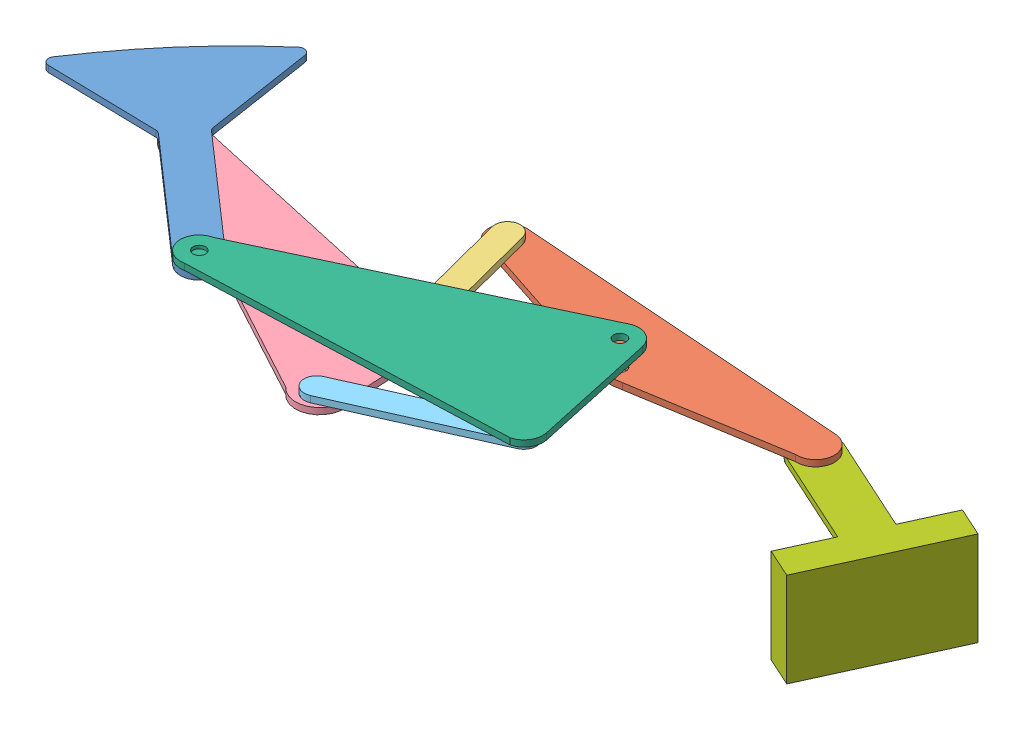
SolidWorks assembly Gait mechanism, configuration Default. Lengths in mm.
Overall size (136.77 20 51.26).
7 component instances, 7 part files, 14 mates.
Components (placement in the parent):
- Link 2-1: Link 2 [Default] at (33.9651 25.6866 73.1492) x (0.753633 0 0.657296) z (-0.657296 0 0.753633) size (44.16 2 29.42)
- Link 4-1: Link 4 [Default] at (98.23 23.6866 61.3566) x (-0.99744 0 -0.071501) z (-0.071501 0 0.99744) size (59 2 11.99)
- Link 6-1: Link 6 [Default] at (74.9428 23.6866 71.5597) x (-0.2516 0 -0.967831) z (0.967831 0 -0.2516) size (32 2 4)
- Link 3-1: Link 3 [Default] at (56.9183 25.6866 85.5418) x (0.87994 0 0.475085) z (0.475085 0 -0.87994) size (58.11 2 18.88)
- Link 1-1: Link 1 [Default] at (91.2887 26.6866 92.8454) x (-0.913376 0 0.407117) z (0.407117 0 0.913376) size (29 2 4)
- Link 5-1: Link 5 [Default] at (57.1662 27.6866 88.6319) x (-0.977094 0 0.212807) z (0.212807 0 0.977094) size (55.17 2 26)
- Leg rest-1: Leg rest [Default] at (141.9026 7.6866 71.1055) x (0.414572 0 -0.910017) z (0.910017 0 0.414572) size (23 15 24.99)
Mates (geometry in assembly coordinates):
- Coincident5: coincident: cylinder of Link 2-1 through (33.9651 24.6866 73.1492) axis (0 1 0) radius 1; circle of Link 3-1
- Coincident7: coincident: plane of Link 2-1 through (52.8059 25.6866 89.5816) normal (0 -1 0); plane of Link 3-1 through (56.9183 25.6866 85.5418) normal (0 1 0)
- Concentric4: concentric: cylinder of Link 6-1 through (78.0878 24.6866 83.6576) axis (0 -1 0) radius 1; cylinder of Link 3-1 through (78.0878 23.6866 83.6576) axis (0 1 0) radius 1
- Coincident8: coincident: plane of Link 6-1 through (74.9428 24.6866 71.5597) normal (0 1 0); plane of Link 3-1 through (56.9183 24.6866 85.5418) normal (0 -1 0)
- Concentric5: concentric: cylinder of Link 3-1 through (79.8715 24.6866 97.9344) axis (0 1 0) radius 1; cylinder of Link 1-1 through (79.8715 24.6866 97.9344) axis (0 1 0) radius 1
- Coincident9: coincident: plane of Link 3-1 through (56.9183 25.6866 85.5418) normal (0 1 0); plane of Link 1-1 through (102.7059 25.6866 87.7565) normal (0 -1 0)
- Concentric11: concentric: cylinder of Link 2-1 through (52.8059 26.6866 89.5816) axis (0 -1 0) radius 1; cylinder of Link 5-1 through (52.8059 26.1866 89.5816) axis (0 1 0) radius 1
- Coincident21: coincident: plane of Link 2-1 through (52.8059 26.6866 89.5816) normal (0 1 0); plane of Link 5-1 through (98.4498 26.6866 68.2146) normal (0 -1 0)
- Concentric12: concentric: cylinder of Link 1-1 through (102.7059 25.6866 87.7565) axis (0 1 0) radius 1; cylinder of Link 5-1 through (102.7059 25.6866 87.7565) axis (0 1 0) radius 1
- Concentric17: concentric: cylinder of Link 4-1 through (124.6621 21.6866 63.2513) axis (0 1 0) radius 1; cylinder of Leg rest-1 through (124.6621 21.6866 63.2513) axis (0 1 0) radius 1
- Coincident27: coincident: plane of Link 4-1 through (98.23 22.6866 61.3566) normal (0 -1 0); plane of Leg rest-1 through (141.9026 22.6866 71.1055) normal (0 1 0)
- Coincident28: coincident: plane of Link 4-1 through (98.23 23.6866 61.3566) normal (0 1 0); plane of Link 6-1 through (74.9428 23.6866 71.5597) normal (0 -1 0)
- Concentric19: concentric: cylinder of Link 4-1 through (98.4498 22.6866 68.2146) axis (0 1 0) radius 1; cylinder of Link 5-1 through (98.4498 26.6866 68.2146) axis (0 1 0) radius 1
- Concentric20: concentric: cylinder of Link 4-1 through (71.7978 22.6866 59.4618) axis (0 1 0) radius 1; cylinder of Link 6-1 through (71.7978 22.6866 59.4618) axis (0 1 0) radius 1
